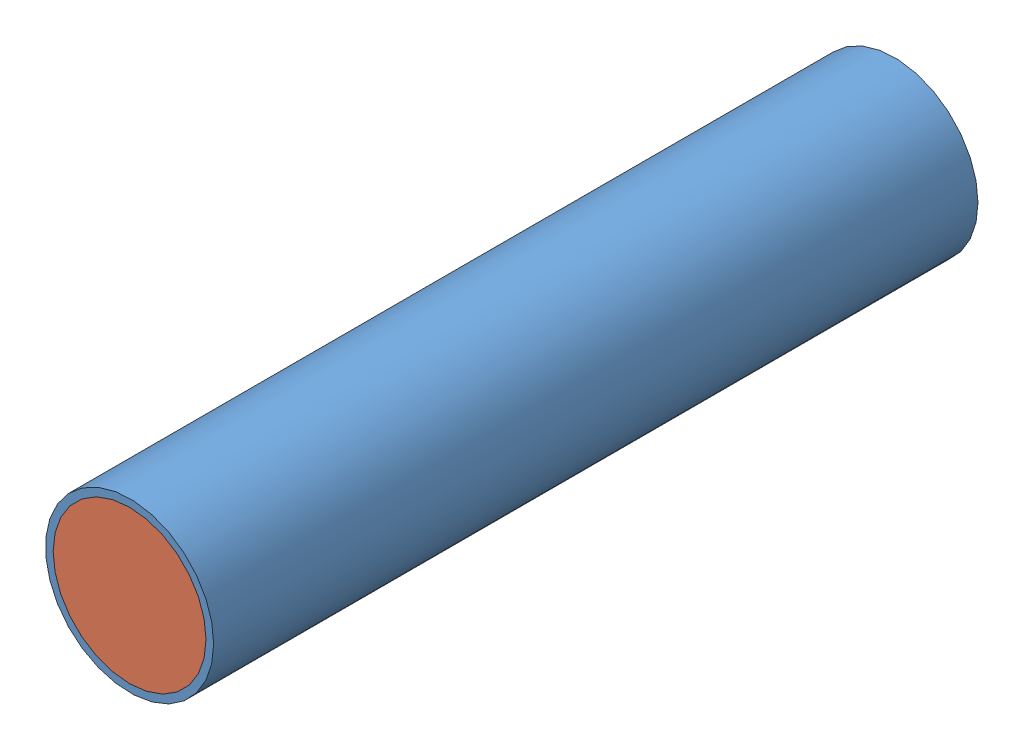
SolidWorks assembly Assem1, configuration Default. Lengths in mm.
Overall size (11 11.02 50).
2 component instances, 2 part files, 4 mates.
Components (placement in the parent):
- BlockedVein-1: BlockedVein [Default] at origin size (11 11.02 50)
- Blood^BlockedVeinCFD-1: Blood^BlockedVeinCFD [Default] at (0 0 25) size (10 10.02 50) (virtual)
Mates (geometry in assembly coordinates):
- InPlace1: in place: plane of BlockedVein-1 through (0 0 25) normal (0 0 1); plane of Blood^BlockedVeinCFD-1 through (0 0 25) normal (0 0 1); moOrthogonalPlaneRef_w of BlockedVein-1 through (0 0 25) normal (0 0 1); plane of Blood^BlockedVeinCFD-1 through (0 0 25) normal (0 1 0); plane of BlockedVein-1 through (0 0 25) normal (0 0 1); plane of Blood^BlockedVeinCFD-1 through (0 0 25) normal (1 0 0); plane of BlockedVein-1 through (0 0 25) normal (0 0 1); unknown of Blood^BlockedVeinCFD-1
- Coincident1: coincident aligned: plane of ?; plane of ?
- Coincident2: coincident aligned: moOrthogonalPlaneRef_w of BlockedVein-1 through (0 0 25) normal (0 1 0); plane of Part2^Assem1-1 through (0 0 25) normal (0 1 0)
- Coincident3: coincident anti-aligned: moOrthogonalPlaneRef_w of BlockedVein-1 through (0 0 25) normal (-1 0 0); plane of Part2^Assem1-1 through (0 0 25) normal (1 0 0)
